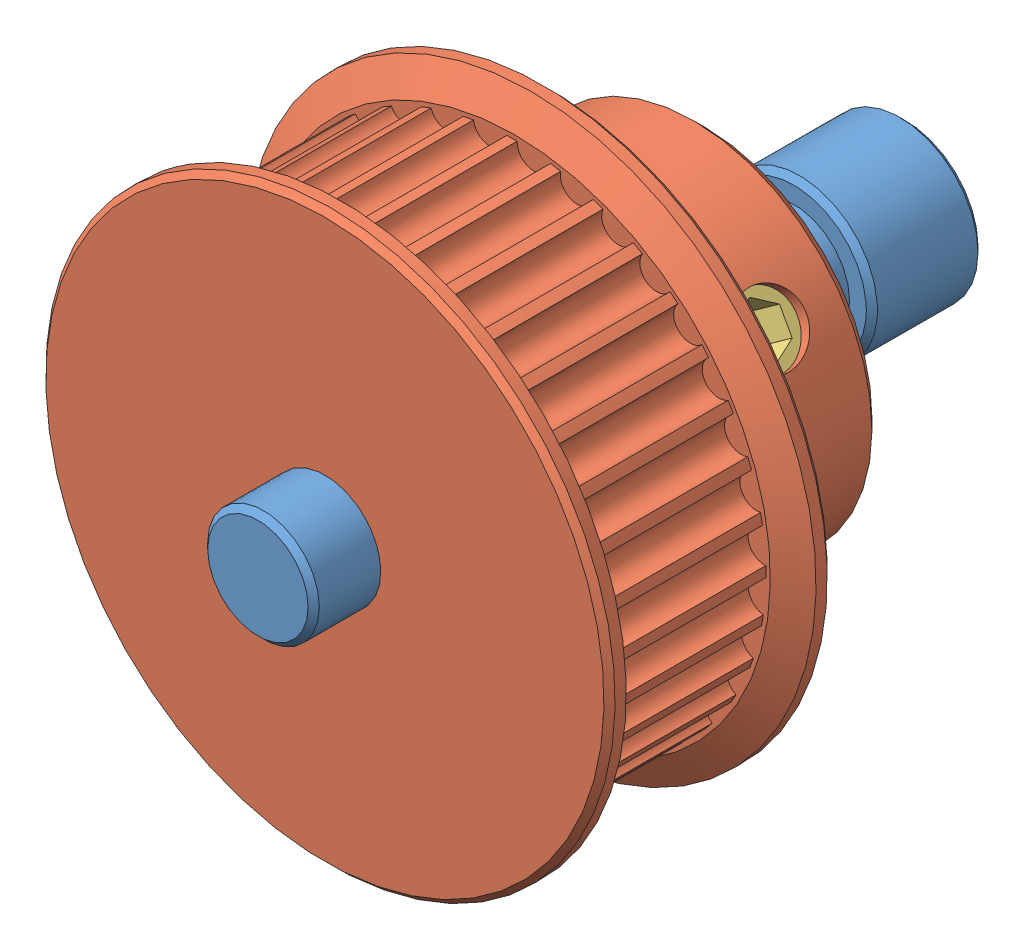
SolidWorks assembly Assieme1, configuration Default. Lengths in mm.
Overall size (35.58 35.58 29).
4 component instances, 3 part files, 6 mates.
Components (placement in the parent):
- albero per ruota condotta-1: albero per ruota condotta [Default] at (12.1553 18.5106 5.0639) size (7 7 29)
- Puleggia-1: Puleggia [Default] at (12.1553 18.5106 14.0639) x (0 0 1) z (-0.582488 0.81284 0) size (17 25.5 25.5)
- socket set screw cone point_iso-1: socket set screw cone point_iso [ISO 4027 - M4 x 5-S] at (7.7867 24.6069 17.5639) x (0.582488 -0.81284 0) z (0.403822 0.289382 -0.867863) size (5 4 4)
- socket set screw cone point_iso-2: socket set screw cone point_iso [ISO 4027 - M4 x 5-S] at (18.2516 22.8793 17.5639) x (-0.81284 -0.582488 0) z (0.245137 -0.342079 0.907133) size (5 4 4)
Mates (geometry in assembly coordinates):
- Concentrico1: concentric aligned: cylinder of albero per ruota condotta-1 through (12.1553 18.5106 34.0639) axis (0 0 -1) radius 2.5; cylinder of Puleggia-1 through (12.1553 18.5106 14.0639) axis (0 0 -1) radius 2.5
- Distanza1: distance = 3 mm aligned: plane of albero per ruota condotta-1 through (12.1553 18.5106 34.0639) normal (0 0 1); plane of Puleggia-1 through (22.519 25.9373 31.0639) normal (0 0 1)
- Concentrico2: concentric anti-aligned: cylinder of Puleggia-1 through (22.5198 25.9379 17.5639) axis (-0.81284 -0.582488 0) radius 1.5; cylinder of socket set screw cone point_iso-2 through (28.5747 30.2768 17.5639) axis (0.81284 0.582488 0) radius 2
- Coincidente1: coincident: cylinder of albero per ruota condotta-1 through (12.1553 18.5106 34.0639) axis (0 0 -1) radius 2.5; point of socket set screw cone point_iso-2
- Concentrico3: concentric anti-aligned: cylinder of Puleggia-1 through (4.728 28.8751 17.5639) axis (0.582488 -0.81284 0) radius 1.5; cylinder of socket set screw cone point_iso-1 through (0.3891 34.93 17.5639) axis (-0.582488 0.81284 0) radius 2
- Coincidente3: coincident: cylinder of albero per ruota condotta-1 through (12.1553 18.5106 34.0639) axis (0 0 -1) radius 2.5; point of socket set screw cone point_iso-1
